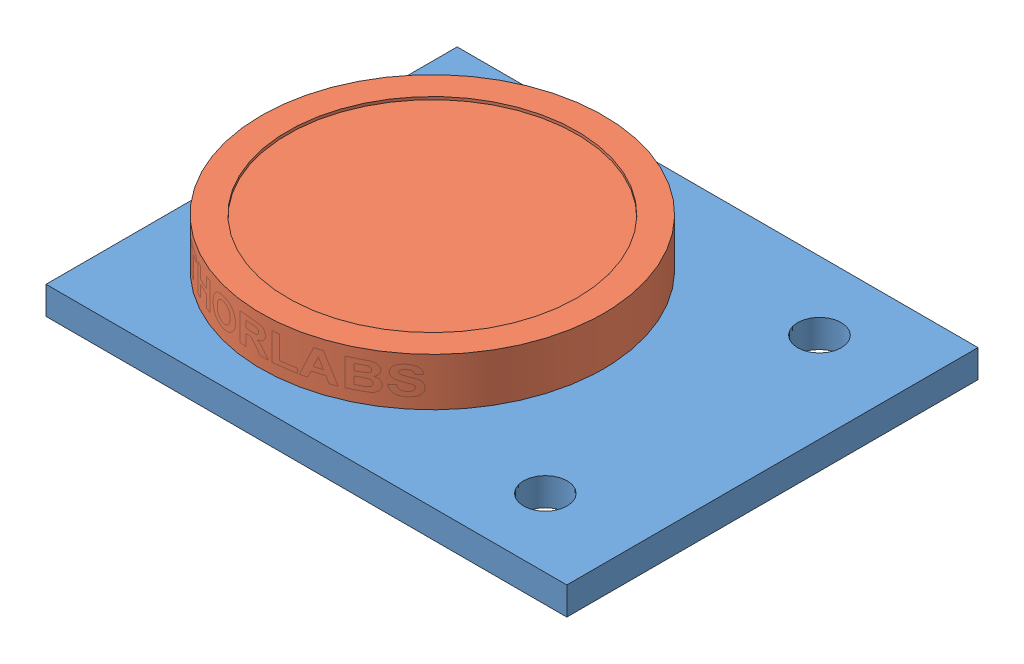
SolidWorks assembly Aperture_with_Bandpass_Filter, configuration Option 2. Lengths in mm.
Overall size (38 5.53 30).
2 component instances, 2 part files, 3 mates.
Components (placement in the parent):
- ApertureStop_Oring-1: ApertureStop_Oring [Default] at (5.8191 18.814 30.5273)
- FLH1030-10-Solidworks-1: FLH1030-10-Solidworks [Default] at (5.8191 22.596 30.5273) x (1 0 0) z (0 -1 0)
Mates (geometry in assembly coordinates):
- Concentric1: concentric anti-aligned: circle of ApertureStop_Oring-1; circle of FLH1030-10-Solidworks-1
- Coincident2: coincident anti-aligned: circle of ApertureStop_Oring-1; circle of FLH1030-10-Solidworks-1
- Coincident3: coincident anti-aligned: circle of ApertureStop_Oring-1; circle of FLH1030-10-Solidworks-1
